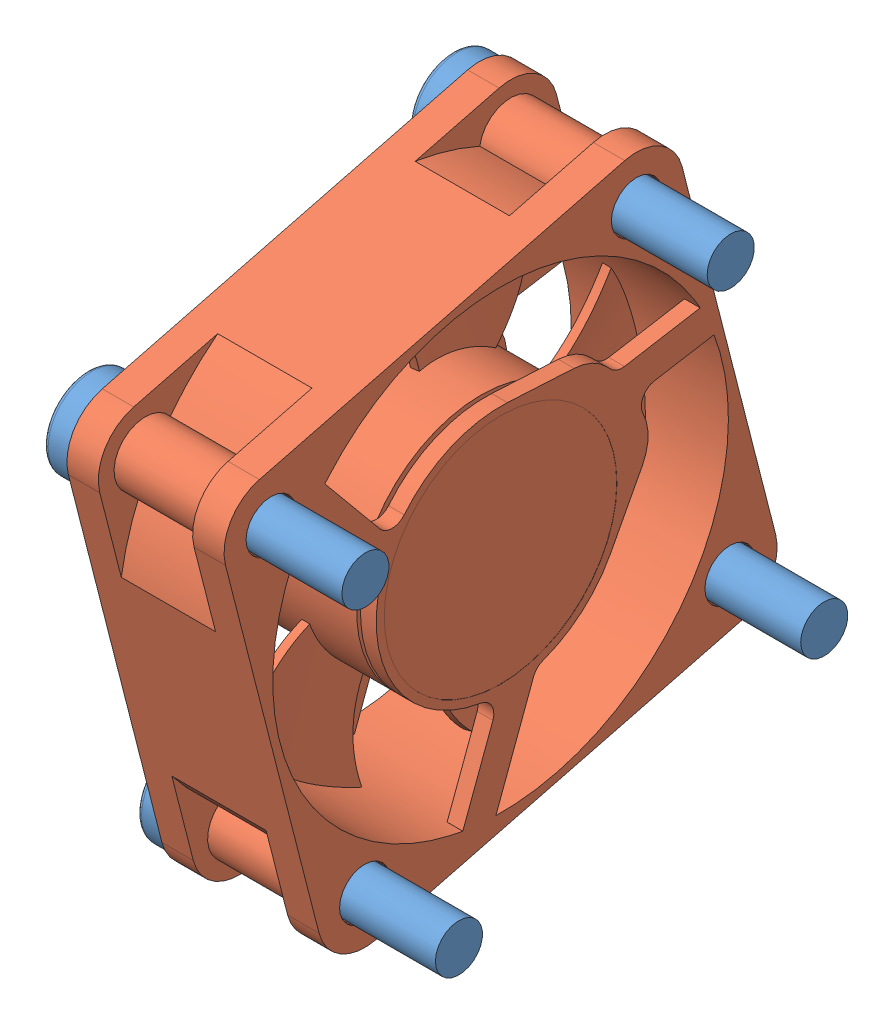
SolidWorks assembly Fan Duct Assembly, configuration Default. Lengths in mm.
Overall size (18.35 38.09 37.92).
6 component instances, 3 part files, 11 mates.
Components (placement in the parent):
- pan head cross recess screw_iso-1: pan head cross recess screw_iso [ISO 7045 - M3 x 16 - Z --- 16N] at (0 -16.5666 -39.5572) size (18.35 5.6 5.6)
- pan head cross recess screw_iso-2: pan head cross recess screw_iso [ISO 7045 - M3 x 16 - Z --- 16N] at (0 6.6834 -33.6044) size (18.35 5.6 5.6)
- pan head cross recess screw_iso-3: pan head cross recess screw_iso [ISO 7045 - M3 x 16 - Z --- 16N] at (0 0.7306 -10.3543) size (18.35 5.6 5.6)
- pan head cross recess screw_iso-4: pan head cross recess screw_iso [ISO 7045 - M3 x 16 - Z --- 16N] at (0 -22.5194 -16.3072) size (18.35 5.6 5.6)
- FAN for Heat Sink (Hotend)-1: FAN for Heat Sink (Hotend) [Default] at (7.4 -7.918 -24.9558) x (0 0.968751 0.248034) z (-1 0 0) size (31.36 31.11 10)
- Fan duct hacked (Hotend)3-1: Fan duct hacked (Hotend)3 [Valor predeterminado] at (27.4 -11.6385 -10.4245) x (1 0 0) z (0 0.968751 0.248034) (suppressed, hidden)
Mates (geometry in assembly coordinates):
- Concentric77: concentric: cylinder of FAN for Heat Sink (Hotend)-1 through (12.4 -16.5666 -39.5572) axis (-1 0 0) radius 1.6; cylinder of pan head cross recess screw_iso-1 through (-25.4 -16.5666 -39.5572) axis (-1 0 0) radius 2.8
- Coincident86: coincident: plane of FAN for Heat Sink (Hotend)-1 through (2.4 2.8927 -6.704) normal (-1 0 0); plane of pan head cross recess screw_iso-1 through (2.4 -15.0666 -39.5572) normal (1 0 0)
- Concentric78: concentric: cylinder of FAN for Heat Sink (Hotend)-1 through (12.4 6.6834 -33.6044) axis (-1 0 0) radius 1.6; cylinder of pan head cross recess screw_iso-2 through (-25.4 6.6834 -33.6044) axis (-1 0 0) radius 2.8
- Coincident87: coincident: plane of FAN for Heat Sink (Hotend)-1 through (2.4 2.8927 -6.704) normal (-1 0 0); plane of pan head cross recess screw_iso-2 through (2.4 8.1834 -33.6044) normal (1 0 0)
- Concentric79: concentric: cylinder of FAN for Heat Sink (Hotend)-1 through (12.4 0.7306 -10.3543) axis (-1 0 0) radius 1.6; cylinder of pan head cross recess screw_iso-3 through (-25.4 0.7306 -10.3543) axis (-1 0 0) radius 2.8
- Coincident88: coincident: plane of FAN for Heat Sink (Hotend)-1 through (2.4 2.8927 -6.704) normal (-1 0 0); plane of pan head cross recess screw_iso-3 through (2.4 2.2306 -10.3543) normal (1 0 0)
- Concentric80: concentric: cylinder of FAN for Heat Sink (Hotend)-1 through (12.4 -22.5194 -16.3072) axis (-1 0 0) radius 1.6; cylinder of pan head cross recess screw_iso-4 through (-25.4 -22.5194 -16.3072) axis (-1 0 0) radius 2.8
- Coincident89: coincident: plane of FAN for Heat Sink (Hotend)-1 through (2.4 2.8927 -6.704) normal (-1 0 0); plane of pan head cross recess screw_iso-4 through (2.4 -21.0194 -16.3072) normal (1 0 0)
- Concentric33: concentric: cylinder of assembly; cone of Fan duct hacked (Hotend)3-1 through (12.4 -16.5666 -39.5572) axis (1 0 0); cylinder of FAN for Heat Sink (Hotend)-1 through (12.4 -16.5666 -39.5572) axis (-1 0 0) radius 1.6
- Concentric34: concentric: cylinder of assembly; cylinder of Fan duct hacked (Hotend)3-1 through (79.2549 0.7306 -10.3543) axis (-1 0 0) radius 1.25; cylinder of FAN for Heat Sink (Hotend)-1 through (12.4 0.7306 -10.3543) axis (-1 0 0) radius 1.6
- Coincident36: coincident: plane of assembly; plane of Fan duct hacked (Hotend)3-1 through (12.4 -26.1698 -14.145) normal (-1 0 0); plane of FAN for Heat Sink (Hotend)-1 through (12.4 2.8927 -6.704) normal (1 0 0)
